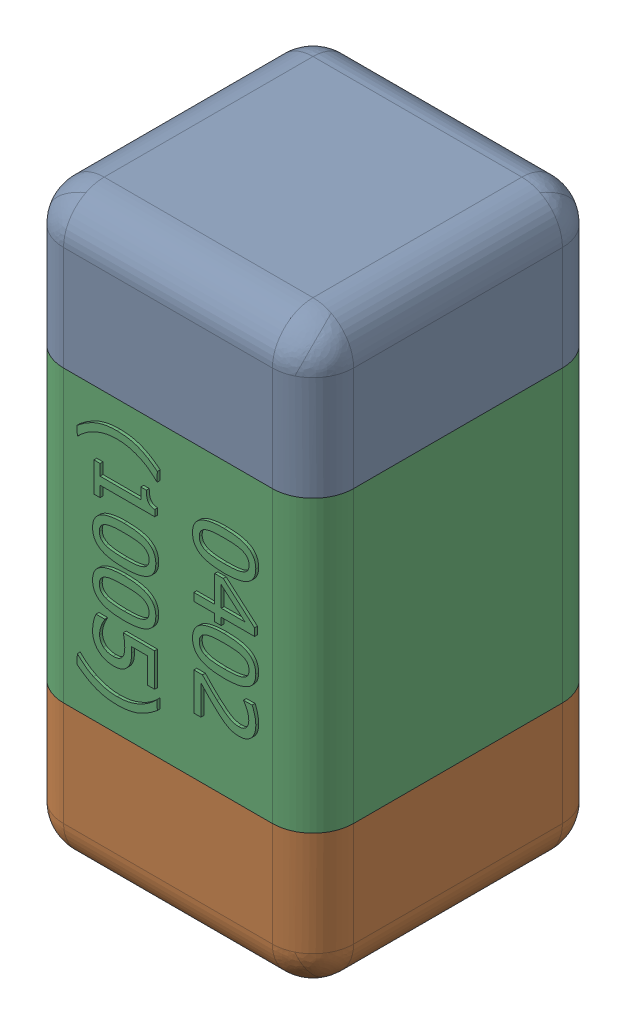
SolidWorks assembly C3, configuration Standard. Lengths in mm.
Overall size (0.51 1.01 0.51).
4 component instances, 3 part files, 0 mates.
Components (placement in the parent):
- C3-subassembly-1-1: C3-subassembly-1 [Standard] at (-4.8 -1.3001 0) x (0 -1 0) z (0 0 1) size (1.01 0.51 0.51)
  - User Library-0402_Cap-1: User Library-0402_Cap [Standard] at origin size (0.26 0.51 0.51)
  - User Library-0402_Cap-1-1: User Library-0402_Cap-1 [Standard] at origin size (0.26 0.5 0.51)
  - User Library-0402_Cap-2-1: User Library-0402_Cap-2 [Standard] at origin size (0.5 0.5 0.51)
